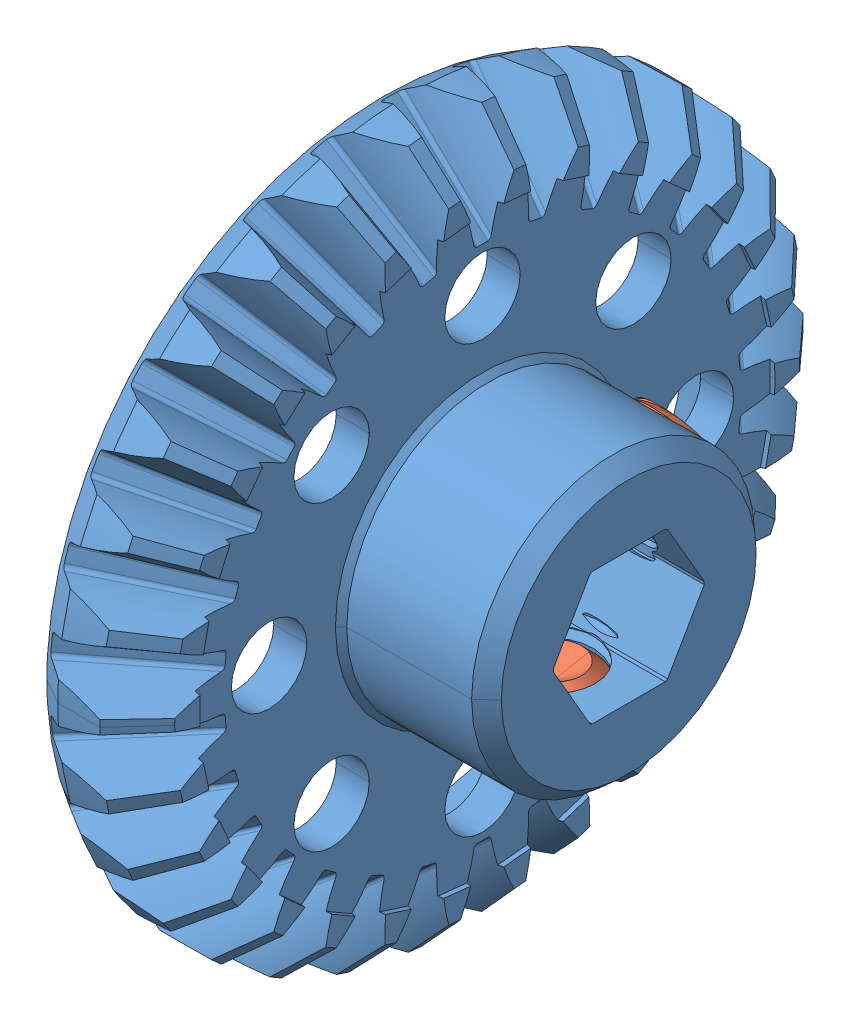
SolidWorks assembly 2315-4008-0030 assembly, configuration 默认. Lengths in mm.
Overall size (13 40.49 40.63).
4 component instances, 2 part files, 0 mates.
Components (placement in the parent):
- 2315-4008-0030 assembly.STEP-1: 2315-4008-0030 assembly.STEP [默认] at origin size (13 40.49 40.63)
  - 2315-4008-0030.STEP-1: 2315-4008-0030.STEP [默认] at (-59.496 22.3782 5.0264) size (13 40.49 40.63)
  - 2806-0005-0004_91390A117.STEP-1: 2806-0005-0004_91390A117.STEP [默认] at (-46.866 25.334 -0.0932) x (0.939121 -0.297554 -0.171793) z (0 0.5 -0.866025) size (5.01 5.01 4.01)
  - 2806-0005-0004_91390A117.STEP-2: 2806-0005-0004_91390A117.STEP [默认] at (-46.866 16.4666 5.0264) x (0.939121 0 0.343586) z (0 -1 0) size (5.01 5.01 4.01)
